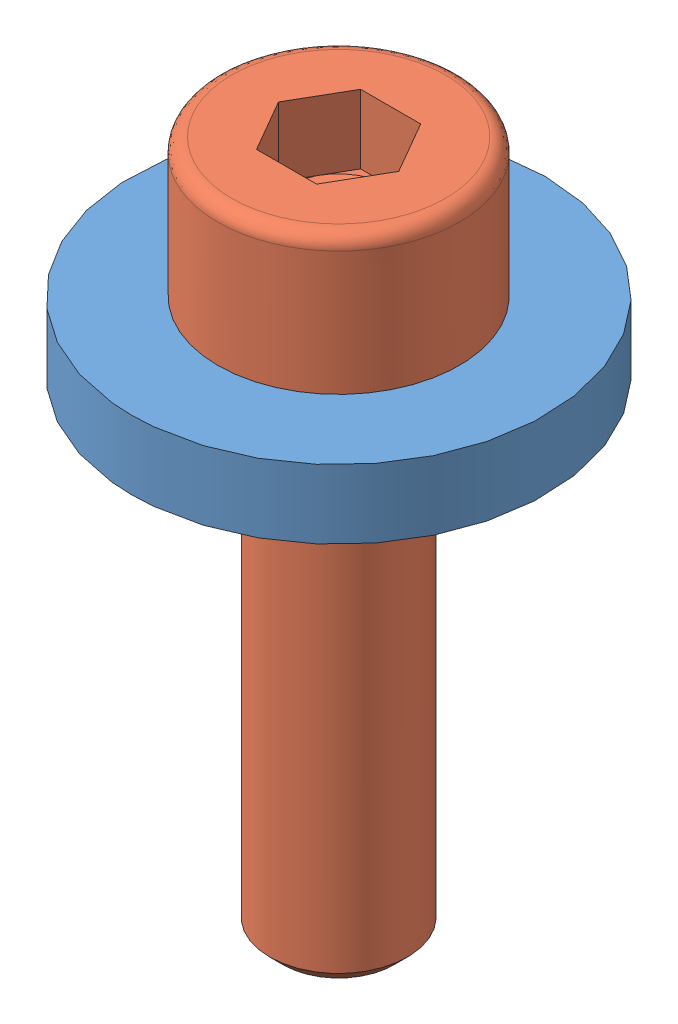
SolidWorks assembly screw_washer, configuration По умолчанию. Lengths in mm.
Overall size (12 20 12).
2 component instances, 2 part files, 2 mates.
Components (placement in the parent):
- Washer_12mm-1: Washer_12mm [По умолчанию] at (-1.0883 -0.773 0.8614) size (12 2 12)
- socket head cap screw_din_1-1: socket head cap screw_din_1 [DIN 912 M4 x 16 --- 16N] at (-1.0883 5.227 0.8614) x (0 -1 0) z (0 0 1) size (20 7 7)
Mates (geometry in assembly coordinates):
- Концентричный1: concentric anti-aligned: cylinder of Washer_12mm-1 through (-1.0883 1.227 0.8614) axis (0 -1 0) radius 2.1; cylinder of socket head cap screw_din_1-1 through (-1.0883 36.977 0.8614) axis (0 1 0) radius 3.5
- Совпадение1: coincident anti-aligned: plane of Washer_12mm-1 through (-1.0883 1.227 0.8614) normal (0 1 0); plane of socket head cap screw_din_1-1 through (2.4117 1.227 0.8614) normal (0 -1 0)
